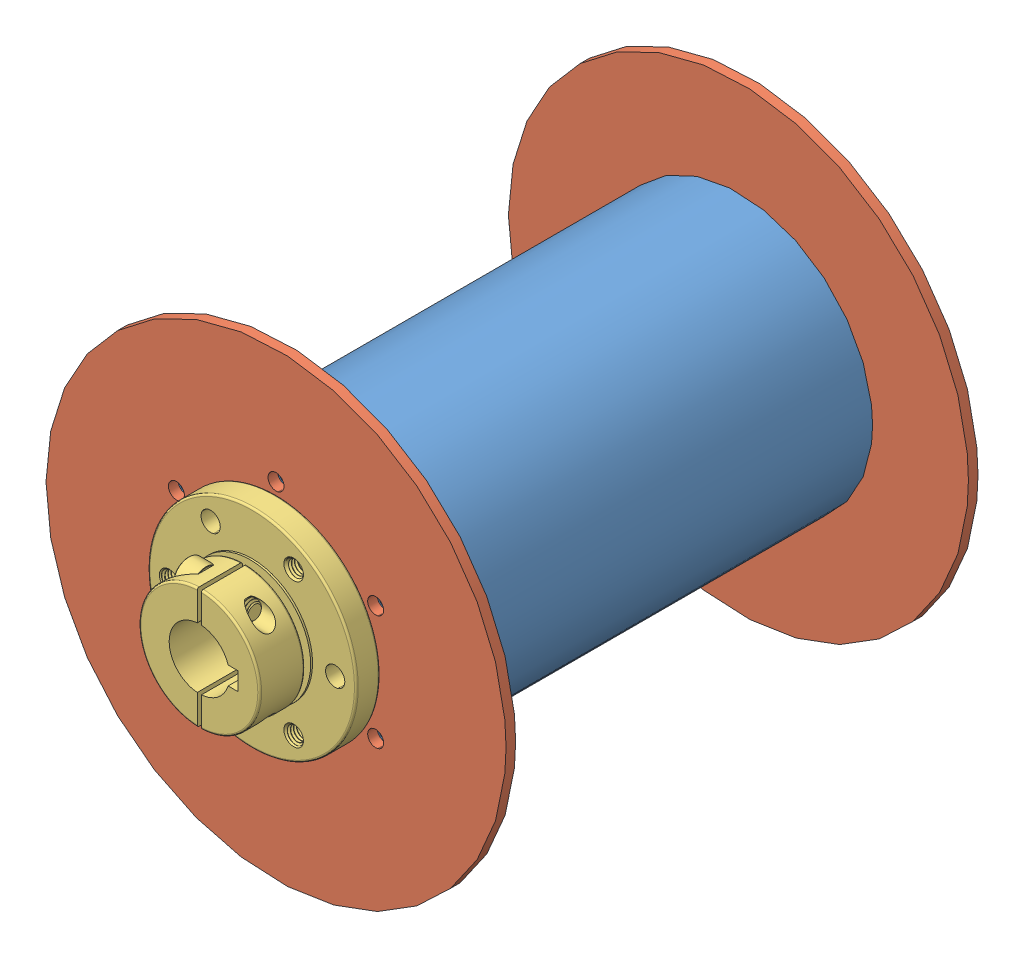
SolidWorks assembly Drum assm, configuration Default. Lengths in mm.
Overall size (152.4 152.4 207.22).
5 component instances, 3 part files, 12 mates.
Components (placement in the parent):
- 3.5in pipe-1: 3.5in pipe [Default] at (35.4917 98.2095 112.414) size (88.9 88.9 150)
- Disk-1: Disk [Default] at (35.4917 98.2095 187.414) size (152.4 152.4 3.17)
- Disk-2: Disk [Default] at (35.4917 98.2095 34.239) size (152.4 152.4 3.17)
- 9604T17_FLANGE-MOUNT SHAFT COLLAR (1)-1: 9604T17_FLANGE-MOUNT SHAFT COLLAR (1) [9604T17] at (35.4917 98.2095 203.289) x (0 0 1) z (-1 0 0) size (25.61 69 69)
- 9604T17_FLANGE-MOUNT SHAFT COLLAR (1)-2: 9604T17_FLANGE-MOUNT SHAFT COLLAR (1) [9604T17] at (35.4917 98.2095 21.539) x (0 0 -1) z (-1 0 0) size (25.61 69 69)
Mates (geometry in assembly coordinates):
- Concentric1: concentric aligned: cylinder of 3.5in pipe-1 through (35.4917 136.3095 187.414) axis (0 0 1) radius 2.1; cylinder of Disk-1 through (35.4917 136.3095 190.589) axis (0 0 1) radius 2.65
- Concentric2: concentric aligned: cylinder of 3.5in pipe-1 through (2.4961 117.2595 187.414) axis (0 0 1) radius 2.1; cylinder of Disk-1 through (2.4961 117.2595 190.589) axis (0 0 1) radius 2.65
- Coincident1: coincident anti-aligned: plane of 3.5in pipe-1 through (35.4917 98.2095 187.414) normal (0 0 1); plane of Disk-1 through (35.4917 98.2095 187.414) normal (0 0 -1)
- Coincident2: coincident anti-aligned: plane of 3.5in pipe-1 through (35.4917 98.2095 37.414) normal (0 0 -1); plane of Disk-2 through (35.4917 98.2095 37.414) normal (0 0 1)
- Concentric3: concentric anti-aligned: cylinder of 3.5in pipe-1 through (2.4961 117.2595 37.414) axis (0 0 -1) radius 2.1; cylinder of Disk-2 through (2.4961 117.2595 37.414) axis (0 0 1) radius 2.65
- Concentric4: concentric anti-aligned: cylinder of 3.5in pipe-1 through (35.4917 136.3095 37.414) axis (0 0 -1) radius 2.1; cylinder of Disk-2 through (35.4917 136.3095 37.414) axis (0 0 1) radius 2.65
- Concentric5: concentric aligned: cylinder of Disk-1 through (21.7417 122.0252 190.589) axis (0 0 1) radius 3.2; cylinder of 9604T17_FLANGE-MOUNT SHAFT COLLAR (1)-1 through (21.7417 122.0252 190.589) axis (0 0 1) radius 3.2
- Concentric6: concentric aligned: cylinder of Disk-1 through (62.9917 98.2095 190.589) axis (0 0 1) radius 3.2; cylinder of 9604T17_FLANGE-MOUNT SHAFT COLLAR (1)-1 through (62.9917 98.2095 190.589) axis (0 0 1) radius 3.2
- Coincident3: coincident anti-aligned: plane of Disk-1 through (35.4917 98.2095 190.589) normal (0 0 1); plane of 9604T17_FLANGE-MOUNT SHAFT COLLAR (1)-1 through (35.4917 108.2095 190.589) normal (0 0 -1)
- Concentric8: concentric anti-aligned: cylinder of 9604T17_FLANGE-MOUNT SHAFT COLLAR (1)-2 through (21.7417 122.0252 34.239) axis (0 0 -1) radius 3.2; cylinder of Disk-2 through (21.7417 122.0252 37.414) axis (0 0 1) radius 3.2
- Coincident4: coincident anti-aligned: plane of Disk-2 through (35.4917 98.2095 34.239) normal (0 0 -1); plane of 9604T17_FLANGE-MOUNT SHAFT COLLAR (1)-2 through (35.4917 88.2095 34.239) normal (0 0 1)
- Concentric9: concentric anti-aligned: cylinder of Disk-2 through (62.9917 98.2095 37.414) axis (0 0 1) radius 3.2; cylinder of 9604T17_FLANGE-MOUNT SHAFT COLLAR (1)-2 through (62.9917 98.2095 34.239) axis (0 0 -1) radius 3.2
